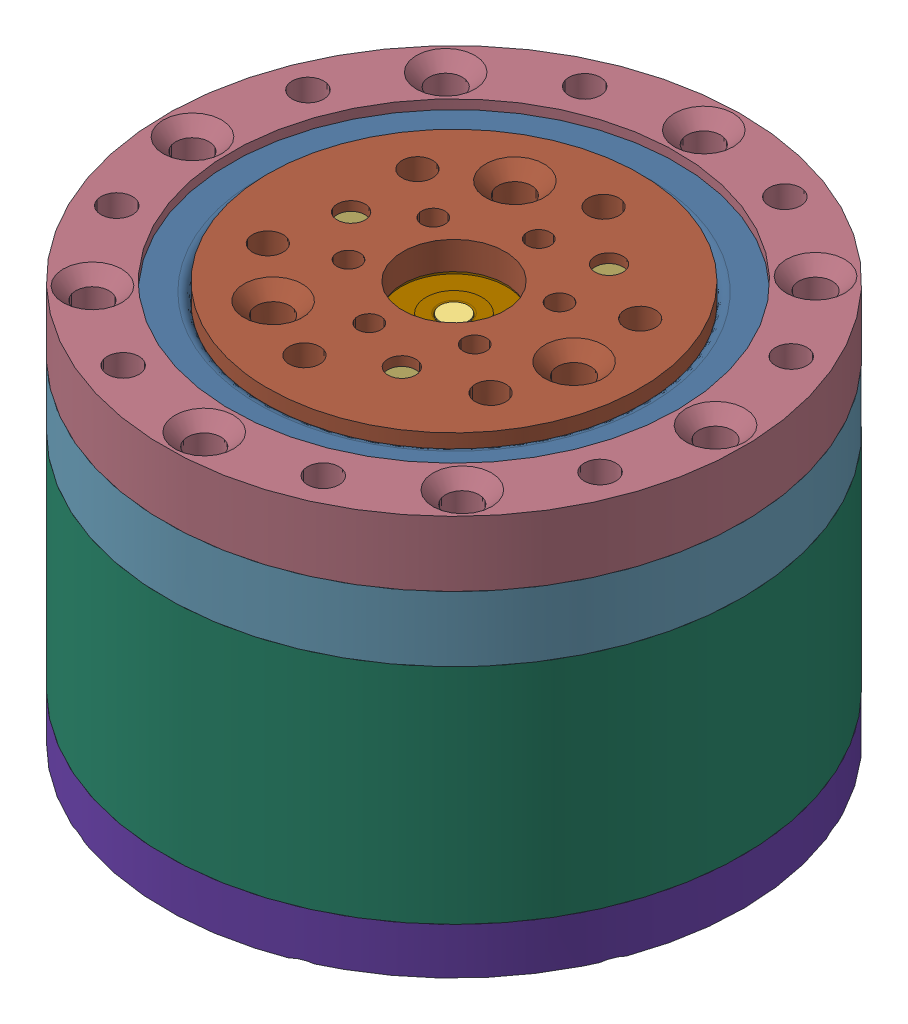
SolidWorks assembly actuator1_tsd, configuration ﾃﾞﾌｫﾙﾄ. Lengths in mm.
Overall size (87.68 44.5 87.68).
26 component instances, 18 part files, 43 mates.
Components (placement in the parent):
- Tarot4008-small-1: Tarot4008-small [ﾃﾞﾌｫﾙﾄ] at (0 14.75 0) x (-0.953045 0 0.302828) z (-0.302828 0 -0.953045) size (50.34 19.01 46.86)
- sun-small_st-1: sun-small_st [ﾃﾞﾌｫﾙﾄ] at (-0.0034 29.5 -0.0037) x (0.996528 0 -0.083255) z (0 1 0) size (6.96 6.96 5)
- Ishaft-small2_al-1: Ishaft-small2_al [ﾃﾞﾌｫﾙﾄ] at (0 24 0) x (0.956118 0 0.29298) z (-0.29298 0 0.956118) size (17 16 17)
- planet-small_st-1: planet-small_st [ﾃﾞﾌｫﾙﾄ] at (-11.9661 29.5 -0.901) x (0.854058 0 -0.520177) z (0 1 0) size (18.99 18.99 5)
- planet-small_st-2: planet-small_st [ﾃﾞﾌｫﾙﾄ] at (6.7634 29.5 -9.9125) x (0.023458 0 0.999725) z (0 1 0) size (18.99 18.99 5)
- planet-small_st-3: planet-small_st [ﾃﾞﾌｫﾙﾄ] at (5.2028 29.5 10.8135) x (-0.877516 0 -0.479548) z (0 1 0) size (18.99 18.99 5)
- ring-small_st-2: ring-small_st [ﾃﾞﾌｫﾙﾄ] at (0 35 0) x (0.999748 0 -0.022428) z (0 -1 0) size (46 46 6)
- CBSTNR3-10-small-1: CBSTNR3-10-small [ﾃﾞﾌｫﾙﾄ] at (1.7579 28.5 -5.7367) x (0 -1 0) z (0.889229 0 0.457463) size (10.8 6 6)
- A-2015-small-1: A-2015-small [ﾃﾞﾌｫﾙﾄ] at (0 28.5 0) x (0 -1 0) z (0.98928 0 -0.146031) size (3.5 20 20)
- CBSTNR3-10-small-2: CBSTNR3-10-small [ﾃﾞﾌｫﾙﾄ] at (-1.7579 28.5 5.7367) x (0 -1 0) z (-0.889229 0 -0.457463) size (10.8 6 6)
- planet-holder-small_al-1: planet-holder-small_al [ﾃﾞﾌｫﾙﾄ] at (0 29 0) x (-0.075085 0 0.997177) z (0 -1 0) size (35 35 10)
- B633ZZ-1: B633ZZ [ﾃﾞﾌｫﾙﾄ] at (-11.9661 34.5 -0.901) x (0 -1 0) z (0.932549 0 -0.361043) size (5 13 13)
- B633ZZ-2: B633ZZ [ﾃﾞﾌｫﾙﾄ] at (6.7634 34.5 -9.9125) x (0 -1 0) z (-0.153602 0 0.988133) size (5 13 13)
- B633ZZ-3: B633ZZ [ﾃﾞﾌｫﾙﾄ] at (5.2028 34.5 10.8135) x (0 -1 0) z (-0.778947 0 -0.627089) size (5 13 13)
- 6708DD_cd3-2: 6708DD_cd3 [ﾃﾞﾌｫﾙﾄ] at (0 36 0) x (0.930417 0 -0.366503) z (0 1 0) size (50 50 6)
- output-plate-small2_al-1: output-plate-small2_al [ﾃﾞﾌｫﾙﾄ] at (0 43 0) x (-0.075085 0 0.997177) z (0 -1 0) size (40.6 40.6 8)
- B633ZZ-4: B633ZZ [ﾃﾞﾌｫﾙﾄ] at (0 40 0) x (0 -1 0) z (0.708855 0 -0.705354) size (5 13 13)
- planet-shaft-small-1: planet-shaft-small [ﾃﾞﾌｫﾙﾄ] at (5.2028 42 10.8135) x (0.34998 0 0.936757) z (0 -1 0) size (3 3 16)
- planet-shaft-small-2: planet-shaft-small [ﾃﾞﾌｫﾙﾄ] at (-11.9661 42 -0.901) x (-0.986245 0 -0.165287) z (0 -1 0) size (3 3 16)
- planet-shaft-small-3: planet-shaft-small [ﾃﾞﾌｫﾙﾄ] at (6.7634 42 -9.9125) x (0.636266 0 -0.77147) z (0 -1 0) size (3 3 16)
- cap-small_3D-1: cap-small_3D [ﾃﾞﾌｫﾙﾄ] at (0 42 0) x (0.690664 0 -0.723176) z (0 -1 0) size (62 62 7)
- ring-holder-small_3D-1: ring-holder-small_3D [ﾃﾞﾌｫﾙﾄ] at (0 29 0) x (0.722788 0 0.69107) z (0 1 0) size (62 62 7)
- housing-small_3D-1: housing-small_3D [ﾃﾞﾌｫﾙﾄ] at (0 29 0) x (-0.71045 0 -0.703747) z (0 -1 0) size (62 62 24)
- magnet-screw-small-1: magnet-screw-small [ﾃﾞﾌｫﾙﾄ] at (0 4.8 0) x (-0.980319 0 0.197418) z (0 -1 0) size (7.79 9 10)
- plate2-small_3D-1: plate2-small_3D [ﾃﾞﾌｫﾙﾄ] at (0 5 0) x (-0.999966 0 0.00829) z (0 -1 0) size (62 62 5.25)
- encoder-1: encoder [ﾃﾞﾌｫﾙﾄ] at (0.0539 -1.5 6.4998) x (0.999966 0 -0.00829) z (0 1 0) size (22 28 1.5)
Mates (geometry in assembly coordinates):
- 同心円1: concentric anti-aligned: cylinder of ring-small_st-2 through (0 29 0) axis (0 1 0) radius 24; cylinder of Tarot4008-small-1 through (0 19.8 0) axis (0 -1 0) radius 22.25
- 一致1: coincident anti-aligned: plane of sun-small_st-1 through (1.9314 29.5 0.5892) normal (-0.974513 0 0.224331); plane of Ishaft-small_al-1 through (1.9321 34.5 0.592) normal (0.974513 0 -0.224331)
- 同心円2: concentric aligned: cylinder of Tarot4008-small-1 through (0 19.8 0) axis (0 -1 0) radius 22.25; cylinder of Ishaft-small_al-1 through (0 28.5 0) axis (0 -1 0) radius 7.5
- 一致3: coincident anti-aligned: plane of Tarot4008-small-1 through (0 24 0) normal (0 1 0); plane of Ishaft-small_al-1 through (0 24 0) normal (0 -1 0)
- 一致5: coincident anti-aligned: plane of sun-small_st-1 through (-1.4843 29.5 1.3755) normal (0.29298 0 -0.956118); plane of Ishaft-small_al-1 through (-1.4787 34.5 1.3772) normal (-0.29298 0 0.956118)
- 一致9: coincident aligned: plane of sun-small_st-1 through (-0.0034 34.5 -0.0037) normal (0 1 0); plane of Ishaft-small_al-1 through (0 34.5 0) normal (0 1 0)
- 同心円4: concentric anti-aligned: cylinder of Ishaft-small_al-1 through (0 28.5 0) axis (0 -1 0) radius 7.5; cylinder of A-2015-small-1 through (0 25 0) axis (0 1 0) radius 7.5
- 一致10: coincident anti-aligned: plane of Ishaft-small_al-1 through (0 25 0) normal (0 1 0); plane of A-2015-small-1 through (1.4384 25 9.7444) normal (0 -1 0)
- 同心円5: concentric aligned: cylinder of Ishaft-small_al-1 through (1.7579 28.5 -5.7367) axis (0 1 0) radius 1.7; cylinder of CBSTNR3-10-small-1 through (1.7579 18.5 -5.7367) axis (0 1 0) radius 1.5
- 一致11: coincident anti-aligned: plane of Ishaft-small_al-1 through (0 28.5 0) normal (0 1 0); plane of CBSTNR3-10-small-1 through (3.1303 28.5 -8.4044) normal (0 -1 0)
- 同心円6: concentric anti-aligned: cylinder of Tarot4008-small-1 through (0 19.8 0) axis (0 -1 0) radius 22.25; cylinder of planet-holder-small_al-1 through (0 25 0) axis (0 1 0) radius 17.5
- 一致12: coincident anti-aligned: plane of A-2015-small-1 through (1.3566 28.5 9.1904) normal (0 1 0); plane of planet-holder-small_al-1 through (0 28.5 0) normal (0 -1 0)
- 同心円7: concentric anti-aligned: cylinder of planet-small_st-1 through (-11.9661 34.5 -0.901) axis (0 -1 0) radius 6.5; cylinder of planet-holder-small_al-1 through (-11.9661 20.7574 -0.901) axis (0 1 0) radius 1.5
- 同心円8: concentric anti-aligned: cylinder of planet-small_st-1 through (-11.9661 34.5 -0.901) axis (0 -1 0) radius 6.5; cylinder of B633ZZ-1 through (-11.9661 29.7 -0.901) axis (0 1 0) radius 6.5
- 一致13: coincident aligned: plane of planet-small_st-1 through (-11.9661 34.5 -0.901) normal (0 1 0); plane of B633ZZ-1 through (-14.2407 34.5 -6.7761) normal (0 1 0)
- 一致15: coincident anti-aligned: plane of ring-small_st-2 through (0 29 0) normal (0 -1 0); plane of planet-holder-small_al-1 through (0 29 0) normal (0 1 0)
- 一致16: coincident anti-aligned: plane of planet-holder-small_al-1 through (-11.9661 29.5 -0.901) normal (0 1 0); plane of B633ZZ-1 through (-12.5799 29.5 -2.4864) normal (0 -1 0)
- 同心円9: concentric anti-aligned: cylinder of Tarot4008-small-1 through (0 19.8 0) axis (0 -1 0) radius 22.25; cylinder of output-plate-small_al-1 through (0 36 0) axis (0 1 0) radius 20
- 同心円10: concentric anti-aligned: cylinder of output-plate-small_al-1 through (0 40 0) axis (0 -1 0) radius 6.5; cylinder of B633ZZ-4 through (0 35.2 0) axis (0 1 0) radius 6.5
- 一致18: coincident anti-aligned: plane of output-plate-small_al-1 through (0 40 0) normal (0 -1 0); plane of B633ZZ-4 through (-4.4437 40 -4.4658) normal (0 1 0)
- 一致20: coincident anti-aligned: plane of Ishaft-small_al-1 through (0 35 0) normal (0 1 0); plane of B633ZZ-4 through (-1.1991 35 -1.2051) normal (0 -1 0)
- 同心円13: concentric anti-aligned: cylinder of 6708DD_cd3-2 through (0 42 0) axis (0 -1 0) radius 20; cylinder of output-plate-small_al-1 through (0 36 0) axis (0 1 0) radius 20
- 一致21: coincident anti-aligned: plane of 6708DD_cd3-2 through (0 36 0) normal (0 -1 0); plane of output-plate-small_al-1 through (0 36 0) normal (0 1 0)
- 同心円14: concentric anti-aligned: cylinder of output-plate-small_al-1 through (5.2028 43 10.8135) axis (0 -1 0) radius 1.5; cylinder of planet-shaft-small-1 through (5.2028 26 10.8135) axis (0 1 0) radius 1.5
- 同心円15: concentric anti-aligned: cylinder of 6708DD_cd3-2 through (0 42 0) axis (0 -1 0) radius 25; cylinder of cap-small_3D-1 through (0 36 0) axis (0 1 0) radius 31
- 同心円16: concentric anti-aligned: cylinder of ring-small_st-2 through (0 29 0) axis (0 1 0) radius 24; cylinder of ring-holder-small_3D-1 through (0 35 0) axis (0 -1 0) radius 31
- 一致23: coincident anti-aligned: plane of ring-small_st-2 through (-22.4784 35 23.5101) normal (0.022428 0 0.999748); plane of ring-holder-small_3D-1 through (0.5158 29 22.9942) normal (-0.022428 0 -0.999748)
- 一致26: coincident anti-aligned: plane of ring-holder-small_3D-1 through (0 29 0) normal (0 -1 0); plane of housing-small_3D-1 through (0 29 0) normal (0 1 0)
- 同心円17: concentric anti-aligned: cylinder of ring-holder-small_3D-1 through (0 35 0) axis (0 -1 0) radius 31; cylinder of housing-small_3D-1 through (0 5 0) axis (0 1 0) radius 31
- 同心円18: concentric aligned: cylinder of Tarot4008-small-1 through (0 9 0) axis (0 -1 0) radius 3; cylinder of magnet-screw-small-1 through (0 10.8 0) axis (0 -1 0) radius 1.5
- 同心円19: concentric aligned: cylinder of housing-small_3D-1 through (0 5 0) axis (0 1 0) radius 31; cylinder of plate2-small_3D-1 through (0 0 0) axis (0 1 0) radius 31
- 一致33: coincident anti-aligned: plane of housing-small_3D-1 through (0 5 0) normal (0 -1 0); plane of plate2-small_3D-1 through (0 5 0) normal (0 1 0)
- 同心円24: concentric: cylinder of housing-small_3D-1 through (0 5 0) axis (0 1 0) radius 31
- 一致36: coincident anti-aligned: plane of plate2-small_3D-1 through (0 0 0) normal (0 -1 0)
- 一致38: coincident aligned: plane of 6708DD_cd3-2 through (0 36 0) normal (0 -1 0); plane of cap-small_3D-1 through (0 36 0) normal (0 -1 0)
- 一致39: coincident anti-aligned: plane of cap-small_3D-1 through (0 36 0) normal (0 -1 0); plane of ring-holder-small_3D-1 through (0 36 0) normal (0 1 0)
- 一致40: coincident anti-aligned: plane of planet-holder-small_al-1 through (0 26 0) normal (0 1 0); plane of planet-shaft-small-1 through (5.2028 26 10.8135) normal (0 -1 0)
- 同心円27: concentric aligned: cylinder of planet-holder-small_al-1 through (5.2028 20.7574 10.8135) axis (0 1 0) radius 1.5; cylinder of planet-shaft-small-1 through (5.2028 26 10.8135) axis (0 1 0) radius 1.5
- 距離1: distance = 23.2 mm anti-aligned: plane of Tarot4008-small-1 through (0 24 0) normal (0 1 0); plane of magnet-screw-small-1 through (0 0.8 0) normal (0 -1 0)
- 同心円28: concentric aligned: cylinder of Tarot4008-small-1 through (-13.7896 10 8.1146) axis (0 -1 0) radius 1.2; cylinder of plate2-small_3D-1 through (-13.7896 0 8.1146) axis (0 -1 0) radius 1.7
- 一致41: coincident anti-aligned: plane of plate2-small_3D-1 through (0 0 0) normal (0 -1 0); plane of encoder-1 through (17.8543 0 -17.6486) normal (0 1 0)
- 同心円29: concentric anti-aligned: cylinder of encoder-1 through (8.9541 0 -5.5744) axis (0 1 0) radius 1.2; cylinder of plate2-small_3D-1 through (8.9541 5 -5.5744) axis (0 -1 0) radius 1.9
- 同心円30: concentric anti-aligned: cylinder of plate2-small_3D-1 through (-9.0453 5 -5.4252) axis (0 -1 0) radius 1.9; cylinder of encoder-1 through (-9.0453 0 -5.4252) axis (0 1 0) radius 1.2
